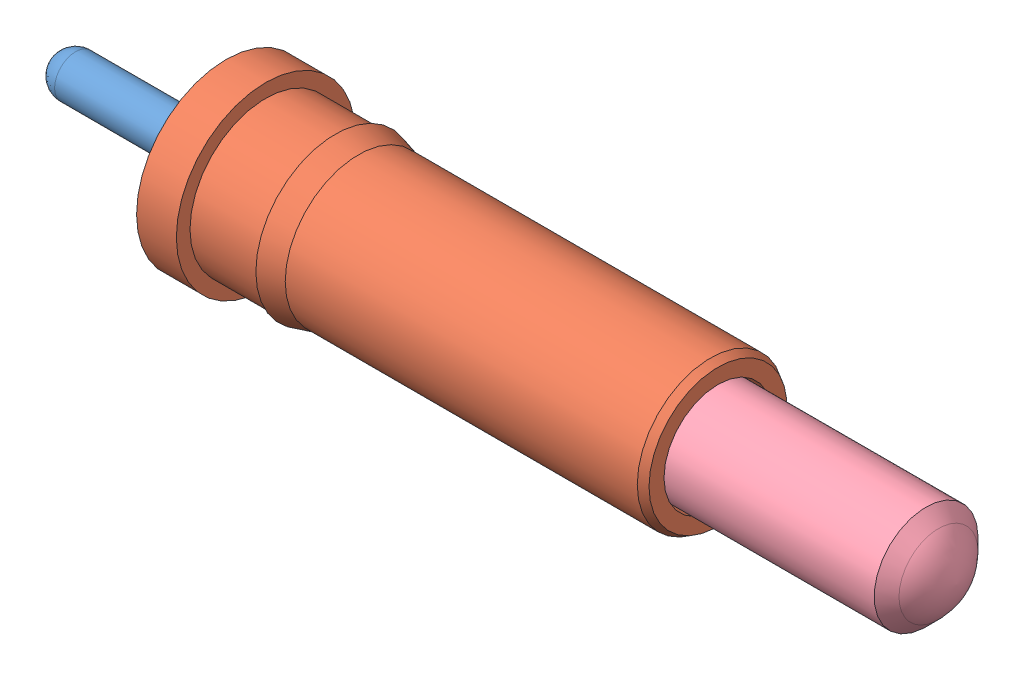
SolidWorks assembly mill-max-0908-2-15-20-75-14-11-0, configuration MillMaxsldprt20150908.29520uGoldoverNickelPage25off. Lengths in mm.
Overall size (9.22 1.83 1.83).
4 component instances, 4 part files, 5 mates.
Components (placement in the parent):
- mill-max-0908-2-15-20-75-14-11-0_0963-0-1: mill-max-0908-2-15-20-75-14-11-0_0963-0 [0963-0-00-20-00-00-13-0] at (0.1795 -0.8235 -1.1087) size (4.04 1.31 1.31)
- mill-max-0908-2-15-20-75-14-11-0_0954-0-1: mill-max-0908-2-15-20-75-14-11-0_0954-0 [0954-0-00-20-00-00-13-0] at (1.9321 -0.8235 -1.1087) size (5.03 1.83 1.83)
- mill-max-0908-2-15-20-75-14-11-0_SPRING-1: mill-max-0908-2-15-20-75-14-11-0_SPRING [0975-0-00-00-75-14-45-0] at (5.5978 -0.8235 -1.1087) x (0 -0.998082 0.061903) z (-1 0 0) size (0.89 1.02 3.43)
- mill-max-0908-2-15-20-75-14-11-0_0918-X-1: mill-max-0908-2-15-20-75-14-11-0_0918-X [0918-7-00-20-00-00-13-0] at (3.9133 -0.8235 -1.1087) x (1 0 0) z (0 0.540629 0.841261) size (5.49 1.25 1.25)
Mates (geometry in assembly coordinates):
- Concentric1: concentric aligned: circle of mill-max-0908-2-15-20-75-14-11-0_0954-0-1; circle of mill-max-0908-2-15-20-75-14-11-0_0963-0-1
- Coincident1: coincident aligned: plane of mill-max-0908-2-15-20-75-14-11-0_0954-0-1 through (1.9321 -0.8235 -1.1087) normal (-1 0 0); plane of mill-max-0908-2-15-20-75-14-11-0_0963-0-1 through (1.9321 -0.5314 -1.1087) normal (-1 0 0)
- Concentric3: concentric aligned: line of mill-max-0908-2-15-20-75-14-11-0_SPRING-1 through (5.5978 -0.8235 -1.1087) axis (-1 0 0); cylinder of mill-max-0908-2-15-20-75-14-11-0_0963-0-1 through (0.1795 -0.8235 -1.1087) axis (-1 0 0) radius 0.2159
- Concentric4: concentric aligned: circle of mill-max-0908-2-15-20-75-14-11-0_0954-0-1; circle of mill-max-0908-2-15-20-75-14-11-0_0918-X-1
- Distance1: distance = 3.048 mm anti-aligned: plane of mill-max-0908-2-15-20-75-14-11-0_0954-0-1 through (6.9613 -0.1182 -1.1087) normal (1 0 0); plane of mill-max-0908-2-15-20-75-14-11-0_0918-X-1 through (3.9133 -0.8235 -1.1087) normal (-1 0 0)
